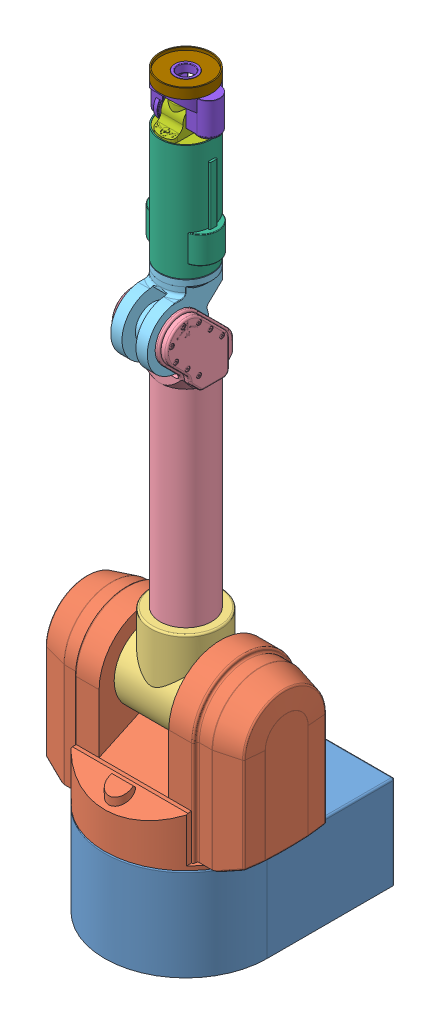
SolidWorks assembly wam, configuration zeroed. Lengths in mm.
Overall size (347.6 1263.13 360).
9 component instances, 9 part files, 13 mates.
Components (placement in the parent):
- B2123_2-1: B2123_2 [Default] at (-45.2708 -95.0327 74.1018)
- B2124_2-1: B2124_2 [Default] at (-45.2708 250.9673 74.1018) x (0 0 1) z (-1 0 0)
- B2125_2-1: B2125_2 [Default] at (-45.2708 250.9673 74.1018) x (-1 0 0) z (0 0 -1)
- B2126_2-1: B2126_2 [Default] at (-45.2708 250.9673 74.1018) x (-1 0 0) z (0 0 -1)
- B2127_2-1: B2127_2 [Default] at (-45.2708 800.9673 119.1018) x (1 0 0) z (0 1 0)
- B2571-1: B2571 [Default] at (-45.2708 873.9673 74.1018) x (-1 0 0) z (0 0 -1)
- B3308-1: B3308 [Default] at (-45.2708 1100.4773 74.1018) x (-1 0 0) z (0 0 -1)
- B2573_2-1: B2573_2 [Default] at (-45.2708 1148.4273 74.1018) x (-1 0 0) z (0 0 -1)
- B2574-1: B2574 [Default] at (-45.2708 1154.4273 74.1018) x (0 0 -1) z (1 0 0)
Mates (geometry in assembly coordinates):
- Coincident30: coordinate: point of B2123_2-1; point of B2124_2-1
- Coincident4: coincident anti-aligned: line of B2123_2-1 through (-45.2708 25.1047 74.1018) axis (0 1 0); line of B2124_2-1 through (-45.2708 386.5901 74.1018) axis (0 -1 0)
- Coincident31: coordinate: point of B2124_2-1; point of B2125_2-1
- Coincident8: coincident anti-aligned: line of B2124_2-1 through (227.3092 250.9673 74.1018) axis (-1 0 0); line of B2125_2-1 through (-105.2708 250.9673 74.1018) axis (1 0 0)
- Coincident32: coordinate: point of B2125_2-1; point of B2126_2-1
- Coincident12: coincident anti-aligned: line of B2125_2-1 through (-45.2708 200.8511 74.1018) axis (0 1 0); line of B2126_2-1 through (-45.2708 531.4674 74.1018) axis (0 -1 0)
- Coincident33: coordinate: point of B2126_2-1; point of B2127_2-1
- Coincident16: coincident aligned: line of B2126_2-1 through (-18.2727 800.9673 119.1018) axis (-1 0 0); line of B2127_2-1 through (5.2029 800.9673 119.1018) axis (-1 0 0)
- Coincident19: coordinate: point of B2127_2-1; point of B2571-1
- Coincident34: coordinate: point of B2571-1; point of B3308-1
- Coincident22: coincident anti-aligned: line of B2571-1 through (-45.2708 873.9282 74.1018) axis (0 1 0); line of B3308-1 through (-45.2708 1119.4773 74.1018) axis (0 -1 0)
- Coincident35: coordinate: point of B3308-1; point of B2573_2-1
- Coincident29: coordinate: point of B2573_2-1; point of B2574-1
